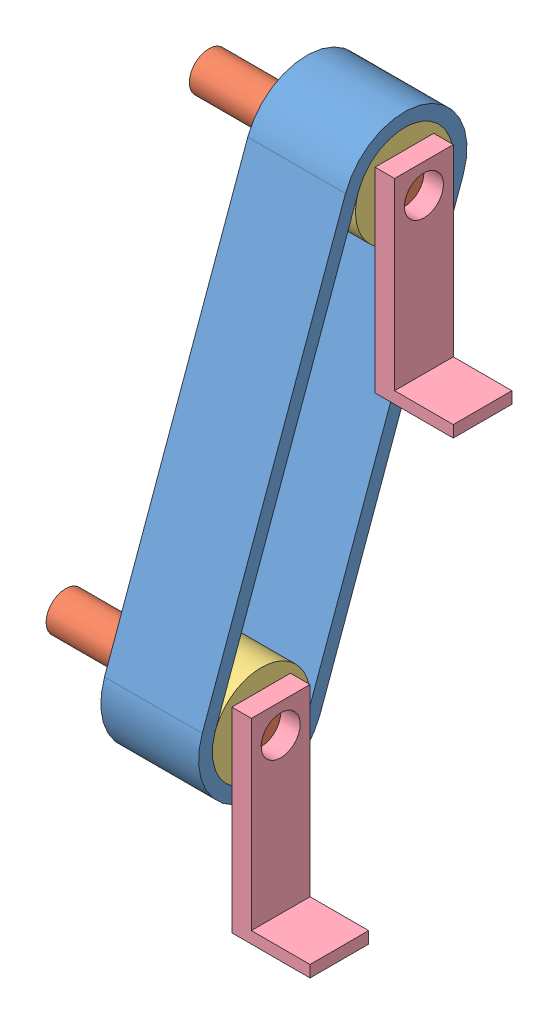
SolidWorks assembly Montagem, configuration Valor predeterminado. Lengths in mm.
Overall size (70 164.26 77.63).
7 component instances, 4 part files, 10 mates.
Components (placement in the parent):
- Couro da Esteira-1: Couro da Esteira [Valor predeterminado] at (5.936 19.5224 38.2456) x (0 -0.940355 0.340195) z (1 0 0) size (139.7 32.02 25)
- Eixo da Esteira-1: Eixo da Esteira [Valor predeterminado] at (-19.064 -77.4853 86.6331) x (0 0 -1) z (1 0 0) size (10 10 50)
- Suporte Esteira-4: Suporte Esteira [Valor predeterminado] at (5.936 23.7748 50) x (0 0 -1) z (1 0 0) size (25 25 25)
- Suporte Esteira-5: Suporte Esteira [Valor predeterminado] at (5.936 -77.4853 86.6331) x (0 0 -1) z (1 0 0) size (25 25 25)
- Eixo da Esteira-2: Eixo da Esteira [Valor predeterminado] at (-19.064 23.7748 50) x (0 0 -1) z (1 0 0) size (10 10 50)
- Base da Esteira-3: Base da Esteira [Valor predeterminado] at (30.936 -119.9853 79.1331) size (20 50 15)
- Base da Esteira-4: Base da Esteira [Valor predeterminado] at (30.936 -18.7252 42.5) size (20 50 15)
Mates (geometry in assembly coordinates):
- Concêntrico3: concentric aligned: cylinder of Couro da Esteira-1 through (30.936 23.7748 50) axis (-1 0 0) radius 12.5; cylinder of Suporte Esteira-4 through (30.936 23.7748 50) axis (-1 0 0) radius 12.5
- Concêntrico4: concentric aligned: cylinder of Couro da Esteira-1 through (30.936 -77.4853 86.6331) axis (-1 0 0) radius 12.5; cylinder of Suporte Esteira-5 through (30.936 -77.4853 86.6331) axis (-1 0 0) radius 12.5
- Coincidente3: coincident aligned: circle of Couro da Esteira-1; circle of Suporte Esteira-4
- Coincidente4: coincident aligned: circle of Couro da Esteira-1; circle of Suporte Esteira-5
- Concêntrico5: concentric aligned: cylinder of Eixo da Esteira-1 through (30.936 -77.4853 86.6331) axis (-1 0 0) radius 5; cylinder of Suporte Esteira-5 through (30.936 -77.4853 86.6331) axis (-1 0 0) radius 5
- Coincidente5: coincident aligned: circle of Eixo da Esteira-1; circle of Suporte Esteira-5
- Concêntrico6: concentric aligned: cylinder of Suporte Esteira-4 through (30.936 23.7748 50) axis (-1 0 0) radius 5; cylinder of Eixo da Esteira-2 through (30.936 23.7748 50) axis (-1 0 0) radius 5
- Coincidente6: coincident aligned: circle of Suporte Esteira-4; circle of Eixo da Esteira-2
- Coincidente9: coincident anti-aligned: circle of Eixo da Esteira-2; circle of Base da Esteira-4
- Coincidente10: coincident anti-aligned: circle of Suporte Esteira-5; circle of Base da Esteira-3
